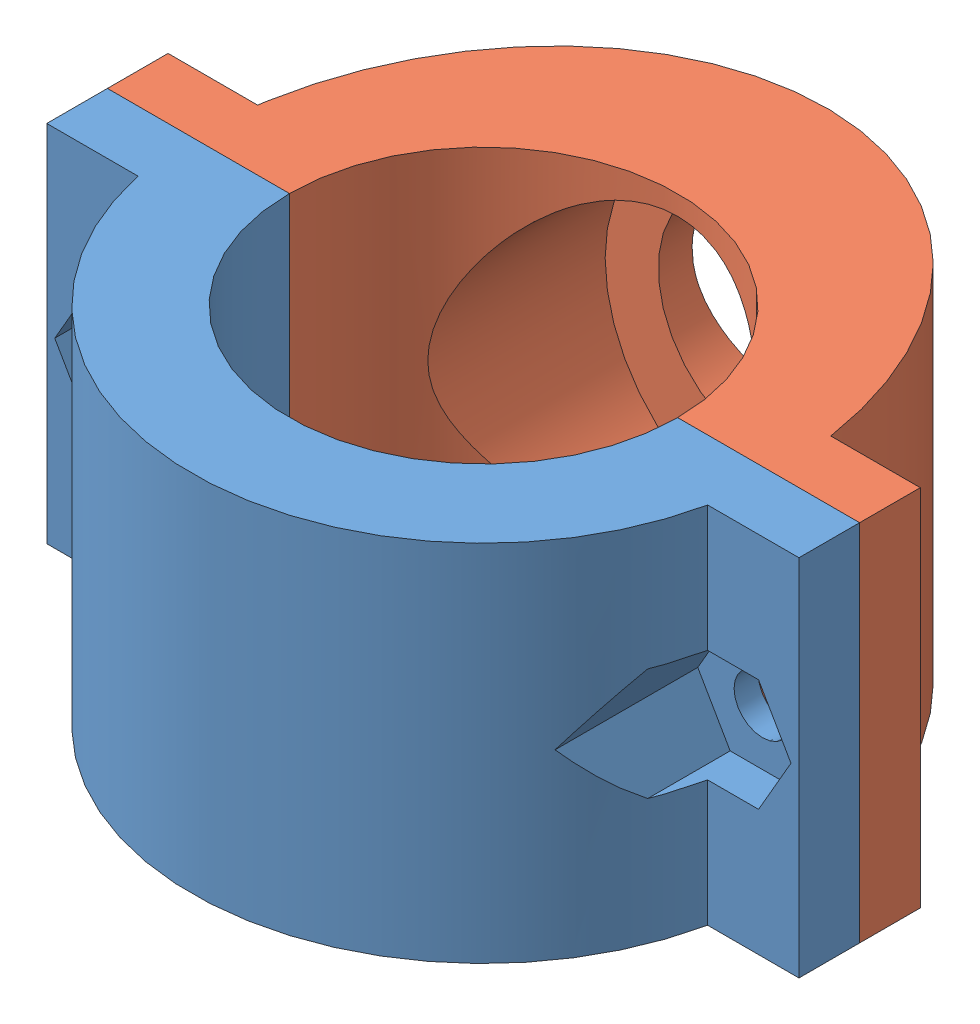
SolidWorks assembly TileHolderV2, configuration Default. Lengths in mm.
Overall size (62 30 52.82).
2 component instances, 2 part files, 6 mates.
Components (placement in the parent):
- tileholderbackv2-2: tileholderbackv2 [Default] at (2.5194 -4.6757 46.5273) size (62 30 24)
- tileholderfrontv2-2: tileholderfrontv2 [Default] at (18.5194 -4.6757 46.5273) x (0 0 1) z (0 1 0) size (28.82 62 30)
Mates (geometry in assembly coordinates):
- Coincident1: coincident: plane of tile holder back v2-1 through (37.2026 44.7456 32.2763) normal (1 0 0); plane of tile holder front v2-1 through (37.2026 44.7456 32.2763) normal (-1 0 0)
- Coincident2: coincident: plane of tile holder back v2-1 through (32.2026 44.7456 79.2763) normal (0 0 1); plane of tile holder front v2-1 through (37.2026 44.7456 79.2763) normal (0 0 1)
- Coincident3: coincident aligned: plane of tile holder back v2-1 through (37.2026 44.7456 48.2763) normal (0 1 0); plane of tile holder front v2-1 through (37.2026 44.7456 48.2763) normal (0 1 0)
- Coincident4: coincident: plane of tileholderbackv2-2 through (34.5194 25.3243 46.5273) normal (0 0 -1); plane of tileholderfrontv2-2 through (34.5194 25.3243 46.5273) normal (0 0 1)
- Coincident6: coincident: plane of tileholderbackv2-2 through (49.5194 25.3243 51.5273) normal (1 0 0); plane of tileholderfrontv2-2 through (49.5194 25.3243 46.5273) normal (1 0 0)
- Coincident7: coincident aligned: plane of tileholderbackv2-2 through (18.5194 25.3243 46.5273) normal (0 1 0); plane of tileholderfrontv2-2 through (18.5194 25.3243 46.5273) normal (0 1 0)
